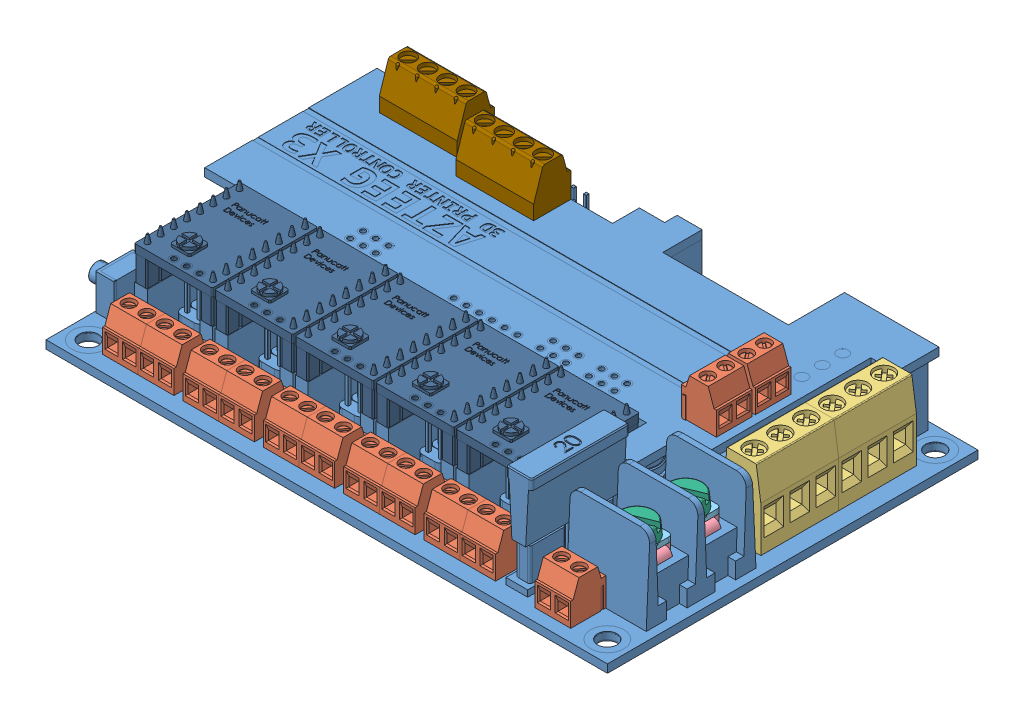
SolidWorks assembly Azteeg X3, configuration Default. Lengths in mm.
Overall size (113.2 25.22 72.75).
37 component instances, 12 part files, 0 mates.
Components (placement in the parent):
- BaseBoard-1: BaseBoard [Default] at (0 0.8 -36.3) x (1 0 0) z (0 1 0) size (113.2 72.75 22.05)
- 2 Way PCB Screw Terminal Block 3_5mm-1: 2 Way PCB Screw Terminal Block 3_5mm [Default] at (-98.5 1.2818 -6.5036) x (-1 0 0) z (0 1 0) size (7.17 6.89 11.02)
- 2 Way PCB Screw Terminal Block 3_5mm-2: 2 Way PCB Screw Terminal Block 3_5mm [Default] at (-60 1.2818 -6.5036) x (-1 0 0) z (0 1 0) size (7.17 6.89 11.02)
- 2 Way PCB Screw Terminal Block 3_5mm-3: 2 Way PCB Screw Terminal Block 3_5mm [Default] at (-91.5 1.2818 -6.5036) x (-1 0 0) z (0 1 0) size (7.17 6.89 11.02)
- 2 Way PCB Screw Terminal Block 3_5mm-4: 2 Way PCB Screw Terminal Block 3_5mm [Default] at (-17.4 15.1 -46.44) x (0 0 1) z (0 1 0) size (7.17 6.89 11.02)
- 2 Way PCB Screw Terminal Block 3_5mm-5: 2 Way PCB Screw Terminal Block 3_5mm [Default] at (-28.5 1.2818 -6.5036) x (-1 0 0) z (0 1 0) size (7.17 6.89 11.02)
- 2 Way PCB Screw Terminal Block 3_5mm-6: 2 Way PCB Screw Terminal Block 3_5mm [Default] at (-51.25 1.2818 -6.5036) x (-1 0 0) z (0 1 0) size (7.17 6.89 11.02)
- 2 Way PCB Screw Terminal Block 3_5mm-7: 2 Way PCB Screw Terminal Block 3_5mm [Default] at (-82.75 1.2818 -6.5036) x (-1 0 0) z (0 1 0) size (7.17 6.89 11.02)
- 2 Way PCB Screw Terminal Block 3_5mm-8: 2 Way PCB Screw Terminal Block 3_5mm [Default] at (-44.25 1.2818 -6.5036) x (-1 0 0) z (0 1 0) size (7.17 6.89 11.02)
- 2 Way PCB Screw Terminal Block 3_5mm-9: 2 Way PCB Screw Terminal Block 3_5mm [Default] at (-75.75 1.2818 -6.5036) x (-1 0 0) z (0 1 0) size (7.17 6.89 11.02)
- 2 Way PCB Screw Terminal Block 3_5mm-10: 2 Way PCB Screw Terminal Block 3_5mm [Default] at (-12.81 1.6 -5.55) x (-1 0 0) z (0 1 0) size (7.17 6.89 11.02)
- 2 Way PCB Screw Terminal Block 3_5mm-11: 2 Way PCB Screw Terminal Block 3_5mm [Default] at (-17.4 15.1 -38.82) x (0 0 1) z (0 1 0) size (7.17 6.89 11.02)
- 2 Way PCB Screw Terminal Block 3_5mm-12: 2 Way PCB Screw Terminal Block 3_5mm [Default] at (-35.5 1.2818 -6.5036) x (-1 0 0) z (0 1 0) size (7.17 6.89 11.02)
- 2 Way PCB Screw Terminal Block 3_5mm-13: 2 Way PCB Screw Terminal Block 3_5mm [Default] at (-67 1.2818 -6.5036) x (-1 0 0) z (0 1 0) size (7.17 6.89 11.02)
- 3 Way PCB Screw Terminal Block 5_08mm-1: 3 Way PCB Screw Terminal Block 5_08mm [Default] at (-12.25 1.6 -33.3) size (9 15.2 15.24)
- 3 Way PCB Screw Terminal Block 5_08mm-2: 3 Way PCB Screw Terminal Block 5_08mm [Default] at (-12.25 1.6 -48.54) size (9 15.2 15.24)
- SWP (Montage draad)-1: SWP (Montage draad) [Default] at (-9.5 10.15 -15.3077) x (0 0 1) z (0 1 0) size (7 9.9 4.25)
- SWP (Montage draad)-2: SWP (Montage draad) [Default] at (-9.5 10.15 -24.8077) x (0 0 1) z (0 1 0) size (7 9.9 4.25)
- SWP (Montage draad 2)-1: SWP (Montage draad 2) [Default] at (-9.5 10.15 -24.8077) x (1 0 0) z (0 1 0) size (7 7 1)
- SWP (Montage draad 2)-2: SWP (Montage draad 2) [Default] at (-9.5 10.15 -15.3077) x (1 0 0) z (0 1 0) size (7 7 1)
- Slotted Cheese Head Screw_DIN_ISO 1207 - M4 x 8 --- 8N-1: Slotted Cheese Head Screw_DIN_ISO 1207 - M4 x 8 --- 8N [Default] at (-9.5 13.75 -24.8077) x (0 -1 0) z (0.926758 0 -0.375659) size (10.61 7 7)
- Slotted Cheese Head Screw_DIN_ISO 1207 - M4 x 8 --- 8N-2: Slotted Cheese Head Screw_DIN_ISO 1207 - M4 x 8 --- 8N [Default] at (-9.5 13.75 -15.3077) x (0 -1 0) z (0.926758 0 -0.375659) size (10.61 7 7)
- Micro SD Slot___ _________-1: Micro SD Slot___ _________ [Default] at (-101 1.6 -41) x (0 0 1) z (-1 0 0) size (14.25 1.9 15.2)
- USB-Mini-B-1: USB-Mini-B [Default] at (-110 3.6 -53.25) x (0 0 1) z (-1 0 0) size (7.7 3.96 9)
- 4 Way PCB Screw Terminal Block 3_81mm_Défaut-1: 4 Way PCB Screw Terminal Block 3_81mm_Défaut [Default] at (-68.91 15.1 -61.75) x (0 0 -1) z (1 0 0) size (7.3 8.5 15.24)
- 4 Way PCB Screw Terminal Block 3_81mm_Défaut-2: 4 Way PCB Screw Terminal Block 3_81mm_Défaut [Default] at (-87.15 15.1 -65) x (0 0 -1) z (1 0 0) size (7.3 8.5 15.24)
- Driver-1: Driver [Default] at (-79.25 16.7 -30.635) x (1 0 0) z (0 1 0) size (15.25 20.7 14.1)
- Driver-2: Driver [Default] at (-63.5 16.7 -30.635) x (1 0 0) z (0 1 0) size (15.25 20.7 14.1)
- Driver-3: Driver [Default] at (-32 16.7 -30.635) x (1 0 0) z (0 1 0) size (15.25 20.7 14.1)
- Driver-4: Driver [Default] at (-47.75 16.7 -30.635) x (1 0 0) z (0 1 0) size (15.25 20.7 14.1)
- Driver-5: Driver [Default] at (-95 16.7 -30.635) x (1 0 0) z (0 1 0) size (15.25 20.7 14.1)
- 3 Way PCB Screw Terminal Block 2.5mm_Défaut-1: 3 Way PCB Screw Terminal Block 2.5mm_Défaut [Default] at (-36.9768 0.3168 -71.7207) x (0 0 -1) z (1 0 0) size (4.79 5.58 7.5)
- 3 Way PCB Screw Terminal Block 2.5mm_Défaut-2: 3 Way PCB Screw Terminal Block 2.5mm_Défaut [Default] at (-20.4768 0.3168 -71.7207) x (0 0 -1) z (1 0 0) size (4.79 5.58 7.5)
- 3 Way PCB Screw Terminal Block 2.5mm_Défaut-3: 3 Way PCB Screw Terminal Block 2.5mm_Défaut [Default] at (-28.7268 0.3168 -71.7207) x (0 0 -1) z (1 0 0) size (4.79 5.58 7.5)
- 2 Way PCB Screw Terminal Block 2.5mm_Défaut-1: 2 Way PCB Screw Terminal Block 2.5mm_Défaut [Default] at (-86.8218 0.3165 -71.7205) x (0 0 -1) z (1 0 0) size (4.79 5.58 5)
- 2 Way PCB Screw Terminal Block 2.5mm_Défaut-2: 2 Way PCB Screw Terminal Block 2.5mm_Défaut [Default] at (-76.3218 0.3165 -71.7205) x (0 0 -1) z (1 0 0) size (4.79 5.58 5)
- 2 Way PCB Screw Terminal Block 2.5mm_Défaut-3: 2 Way PCB Screw Terminal Block 2.5mm_Défaut [Default] at (-81.5718 0.3165 -71.7205) x (0 0 -1) z (1 0 0) size (4.79 5.58 5)
